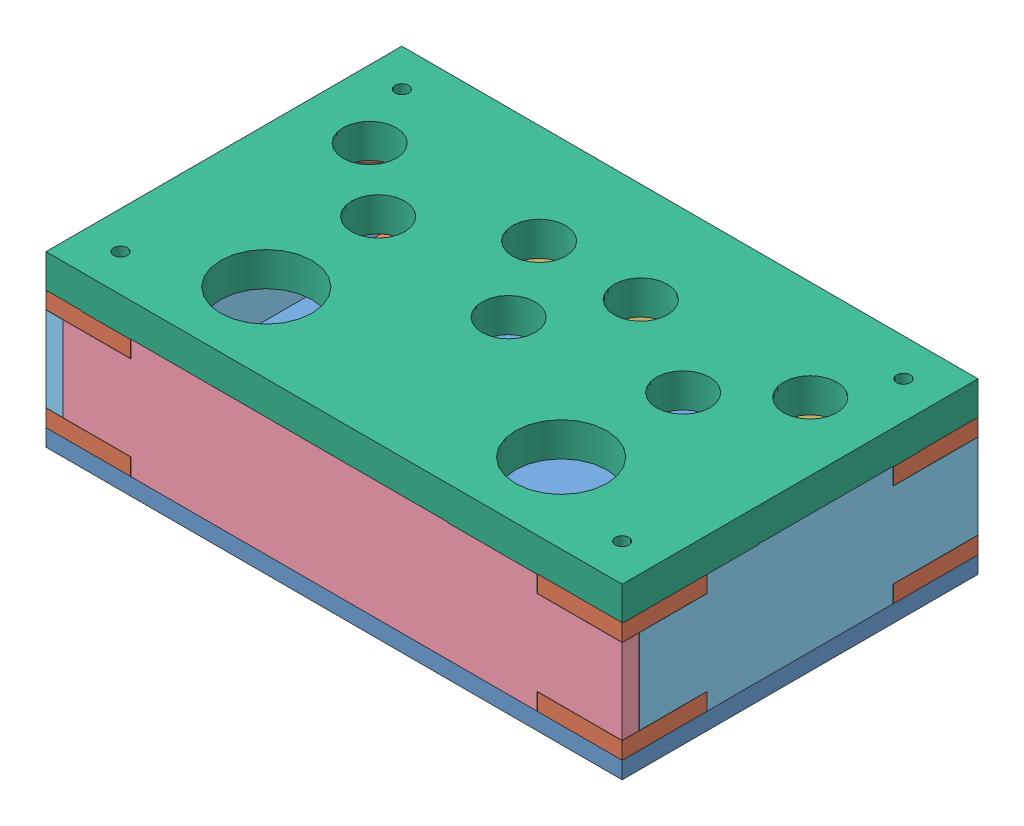
SolidWorks assembly Assem1, configuration ﾃﾞﾌｫﾙﾄ. Lengths in mm.
Overall size (170 49.98 105).
14 component instances, 6 part files, 27 mates.
Components (placement in the parent):
- 下-1: 下 [ﾃﾞﾌｫﾙﾄ] at (-17.5315 74.0908 187.4112) size (170 5 105)
- 角-1: 角 [ﾃﾞﾌｫﾙﾄ] at (-17.5315 79.0908 187.4112) size (25 5 25)
- 後-1: 後 [ﾃﾞﾌｫﾙﾄ] at (147.3985 84.1608 87.4112) x (-1 0 0) z (0 0 -1) size (164.93 35.14 5)
- 前-1: 前 [ﾃﾞﾌｫﾙﾄ] at (-12.4615 84.1608 182.4112) size (164.93 35.14 5)
- 角-2: 角 [ﾃﾞﾌｫﾙﾄ] at (152.4685 84.0908 82.4112) x (0 0 1) z (1 0 0) size (25 5 25)
- 角-6: 角 [ﾃﾞﾌｫﾙﾄ] at (-17.5315 79.0908 82.4112) x (0 0 1) z (-1 0 0) size (25 5 25)
- 角-7: 角 [ﾃﾞﾌｫﾙﾄ] at (152.4685 79.0908 187.4112) x (0 0 -1) z (1 0 0) size (25 5 25)
- 左右-1: 左右 [ﾃﾞﾌｫﾙﾄ] at (-12.5315 84.1608 87.4812) x (0 0 1) z (-1 0 0) size (99.93 35.14 5)
- 左右-2: 左右 [ﾃﾞﾌｫﾙﾄ] at (147.4685 84.1608 182.3412) x (0 0 -1) z (1 0 0) size (99.93 35.14 5)
- 上-1: 上 [ﾃﾞﾌｫﾙﾄ] at (-17.5315 114.0671 187.4112) size (170 10 105)
- 角-8: 角 [ﾃﾞﾌｫﾙﾄ] at (-17.5315 109.2308 187.4112) size (25 5 25)
- 角-9: 角 [ﾃﾞﾌｫﾙﾄ] at (152.4685 109.2308 187.4112) x (0 0 -1) z (1 0 0) size (25 5 25)
- 角-10: 角 [ﾃﾞﾌｫﾙﾄ] at (-17.5315 109.2308 82.4112) x (0 0 1) z (-1 0 0) size (25 5 25)
- 角-11: 角 [ﾃﾞﾌｫﾙﾄ] at (152.4685 109.2308 82.4112) x (-1 0 0) z (0 0 -1) size (25 5 25)
Mates (geometry in assembly coordinates):
- 一致1: coincident anti-aligned: line of 角-6 through (-17.5315 79.0908 82.4112) axis (0 0 1); line of 下-1 through (-17.5315 79.0908 187.4112) axis (0 0 -1)
- 一致2: coincident aligned: line of 下-1 through (-17.5315 79.0908 82.4112) axis (1 0 0); line of 角-6 through (-17.5315 79.0908 82.4112) axis (1 0 0)
- 一致3: coincident aligned: line of 下-1 through (-17.5315 79.0908 187.4112) axis (0 0 -1); line of 角-1 through (-17.5315 79.0908 187.4112) axis (0 0 -1)
- 一致8: coincident anti-aligned: line of 下-1 through (-17.5315 79.0908 187.4112) axis (1 0 0); line of 角-7 through (152.4685 79.0908 187.4112) axis (-1 0 0)
- 一致9: coincident aligned: line of 下-1 through (152.4685 79.0908 187.4112) axis (0 0 -1); line of 角-7 through (152.4685 79.0908 187.4112) axis (0 0 -1)
- 一致10: coincident aligned: line of 下-1 through (-17.5315 79.0908 187.4112) axis (1 0 0); line of 角-1 through (-17.5315 79.0908 187.4112) axis (1 0 0)
- 一致11: coincident anti-aligned: line of 下-1 through (152.4685 79.0908 187.4112) axis (0 0 -1); line of 角-2 through (152.4685 79.0908 82.4112) axis (0 0 1)
- 一致12: coincident anti-aligned: line of 下-1 through (-17.5315 79.0908 82.4112) axis (1 0 0); line of 角-2 through (152.4685 79.0908 82.4112) axis (-1 0 0)
- 一致20: coincident anti-aligned: line of 前-1 through (152.4685 84.1608 187.4112) axis (0 1 0); line of 角-7 through (152.4685 84.0908 187.4112) axis (0 -1 0)
- 一致24: coincident anti-aligned: line of 角-1 through (-17.5315 84.0908 187.4112) axis (0 -1 0); line of 左右-1 through (-17.5315 84.1608 187.4112) axis (0 1 0)
- 一致25: coincident aligned: line of 下-1 through (-17.5315 79.0908 187.4112) axis (0 0 -1); line of 左右-1 through (-17.5315 79.0908 162.3412) axis (0 0 -1)
- 一致27: coincident anti-aligned: line of 後-1 through (-17.5315 84.1608 82.4112) axis (0 1 0); line of 角-6 through (-17.5315 84.0908 82.4112) axis (0 -1 0)
- 一致28: coincident aligned: line of 角-2 through (152.4685 79.0908 82.4112) axis (0 1 0); line of 左右-2 through (152.4685 84.1608 82.4112) axis (0 1 0)
- 一致30: coincident anti-aligned: line of 下-1 through (152.4685 79.0908 187.4112) axis (0 0 -1); line of 左右-2 through (152.4685 79.0908 107.4812) axis (0 0 1)
- 一致31: coincident anti-aligned: line of 前-1 through (152.4685 84.1608 187.4112) axis (0 1 0); line of 角-9 through (152.4685 114.2308 187.4112) axis (0 -1 0)
- 一致33: coincident aligned: line of 左右-1 through (-17.5315 114.2308 162.3412) axis (0 0 -1); line of 角-8 through (-17.5315 114.2308 187.4112) axis (0 0 -1)
- 一致37: coincident aligned: line of 前-1 through (127.3985 114.2308 187.4112) axis (-1 0 0); line of 角-9 through (152.4685 114.2308 187.4112) axis (-1 0 0)
- 一致39: coincident anti-aligned: line of 左右-1 through (-17.5315 84.1608 187.4112) axis (0 1 0); line of 角-8 through (-17.5315 114.2308 187.4112) axis (0 -1 0)
- 平行5: parallel anti-aligned: line of 左右-1 through (-17.5315 114.2308 162.3412) axis (0 0 -1); line of 角-10 through (-17.5315 114.2308 82.4112) axis (0 0 1)
- 平行8: parallel aligned: line of 左右-2 through (152.4685 114.2308 107.4812) axis (0 0 1); line of 角-11 through (152.4685 114.2308 82.4112) axis (0 0 1)
- 一致46: coincident anti-aligned: line of 左右-2 through (152.4685 84.1608 82.4112) axis (0 1 0); line of 角-11 through (152.4685 114.2308 82.4112) axis (0 -1 0)
- 一致48: coincident aligned: line of 左右-2 through (152.4685 114.2308 107.4812) axis (0 0 1); line of 角-11 through (152.4685 114.2308 82.4112) axis (0 0 1)
- 同心円1: concentric anti-aligned: cylinder of 上-1 through (141.4685 124.0671 93.4112) axis (0 -1 0) radius 2; circle of 角-11
- 同心円2: concentric aligned: circle of 上-1; circle of 角-10
- 一致49: coincident anti-aligned: line of 前-1 through (127.3985 114.2308 187.4112) axis (-1 0 0); line of 角-8 through (-17.5315 114.2308 187.4112) axis (1 0 0)
- 一致50: coincident anti-aligned: line of 後-1 through (7.5385 114.2308 82.4112) axis (1 0 0); line of 角-11 through (152.4685 114.2308 82.4112) axis (-1 0 0)
- 一致51: coincident aligned: line of 後-1 through (7.5385 114.2308 82.4112) axis (1 0 0); line of 角-10 through (-17.5315 114.2308 82.4112) axis (1 0 0)
